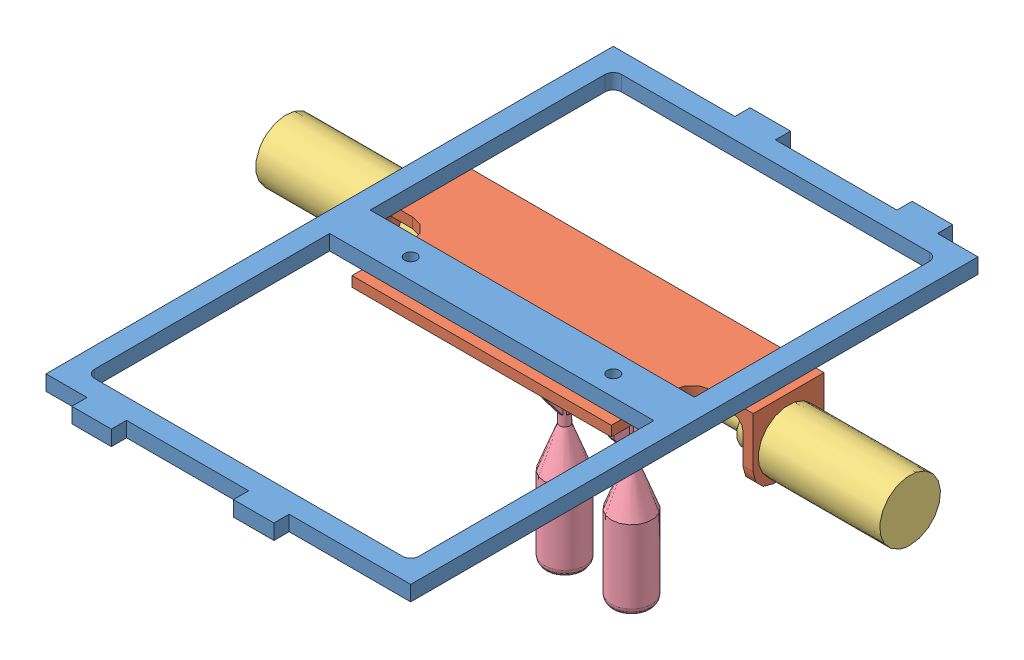
SolidWorks assembly Assem1, configuration Default. Lengths in mm.
Overall size (195.58 86.04 187.33).
9 component instances, 5 part files, 3 mates.
Components (placement in the parent):
- Dropper Panel-1: Dropper Panel [Default] at (-46.6714 28.2575 3.8123) size (114.3 4.76 187.33)
- torpedo_bay-1: torpedo_bay [Default] at (-44.5892 27.5269 -58.8843) size (195.58 81.98 49.92)
  - torpedo_bay-1: torpedo_bay [Default] at (-2.0822 -27.8444 35.7091) size (119.38 22.23 47.63)
  - solenoid_dropper-1: solenoid_dropper [Default] at (57.6078 -11.9694 35.7091) x (0 -0.981452 0.191707) z (1 0 0) size (19.05 19.05 66.8)
  - torpedo-1: torpedo [Default] at (-12.5597 -80.5467 35.7091) size (12.7 72.39 12.7)
  - torpedo-2: torpedo [Default] at (8.3953 -80.5467 35.7091) x (-1 0 0) z (0 0 -1) size (12.7 72.39 12.7)
  - torpedo pin-1: torpedo pin [Default] at (11.9498 -11.9694 35.7091) x (0 0.461361 0.887212) z (0 0.887212 -0.461361) size (4.57 33.02 4.57)
  - torpedo pin-2: torpedo pin [Default] at (-16.1142 -11.6769 35.4353) x (0 0.684501 0.729012) z (0 -0.729012 0.684501) size (4.57 33.02 4.57)
  - solenoid_dropper-3: solenoid_dropper [Default] at (-61.7722 -11.9694 35.7091) x (0 0.633707 0.773573) z (-1 0 0) size (19.05 19.05 66.8)
Mates (geometry in assembly coordinates):
- Concentric1: concentric: circle of Dropper Panel-1; circle of torpedo_bay-1/torpedo_bay-1
- Concentric2: concentric: circle of Dropper Panel-1; circle of torpedo_bay-1/torpedo_bay-1
- Coincident3: coincident anti-aligned: plane of Dropper Panel-1 through (-103.8214 28.2575 92.7123) normal (0 -1 0); plane of torpedo_bay-1/torpedo_bay-1 through (-106.3614 28.2575 -12.0627) normal (0 1 0)
